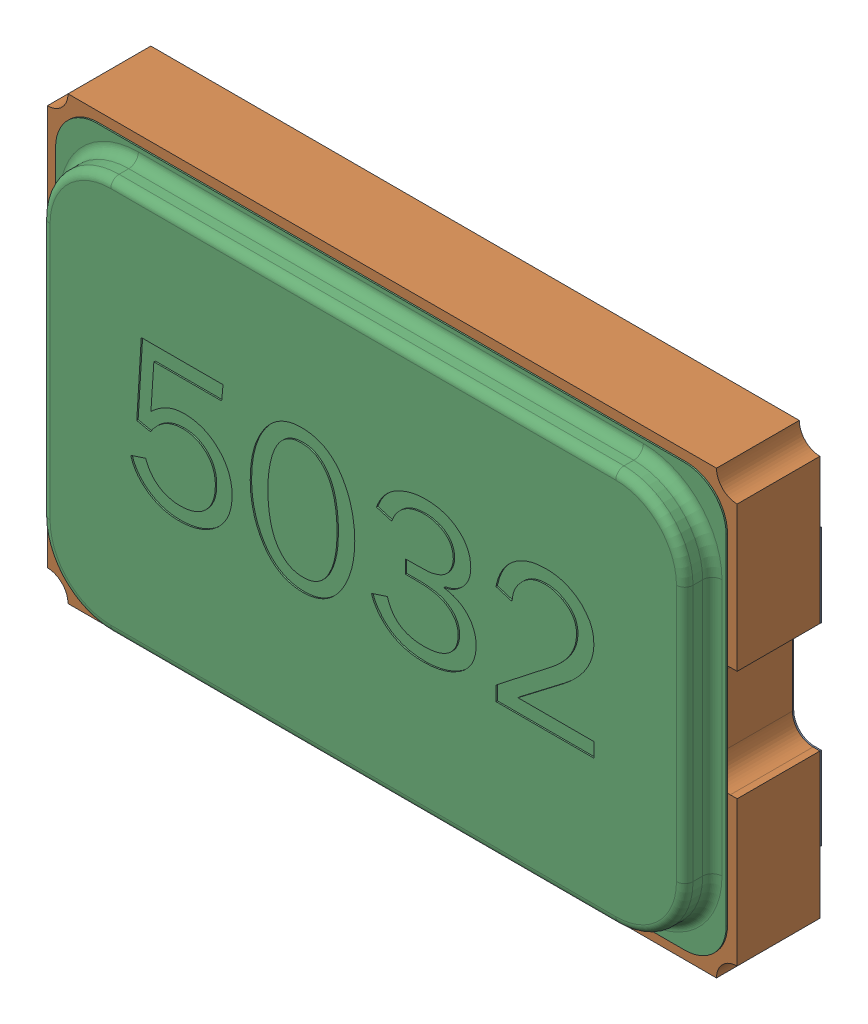
SolidWorks assembly OSC_5032-2, configuration 默认. Lengths in mm.
Overall size (5 3.2 0.82).
2 component instances, 2 part files, 0 mates.
Components (placement in the parent):
- OSC_5032-2-1: OSC_5032-2 [默认] at origin size (5 3.2 0.82)
- LOGO_0.5-1: LOGO_0.5 [默认] at (-0.0001 0.1135 0.045) size (1.5 1.73 0.01)
